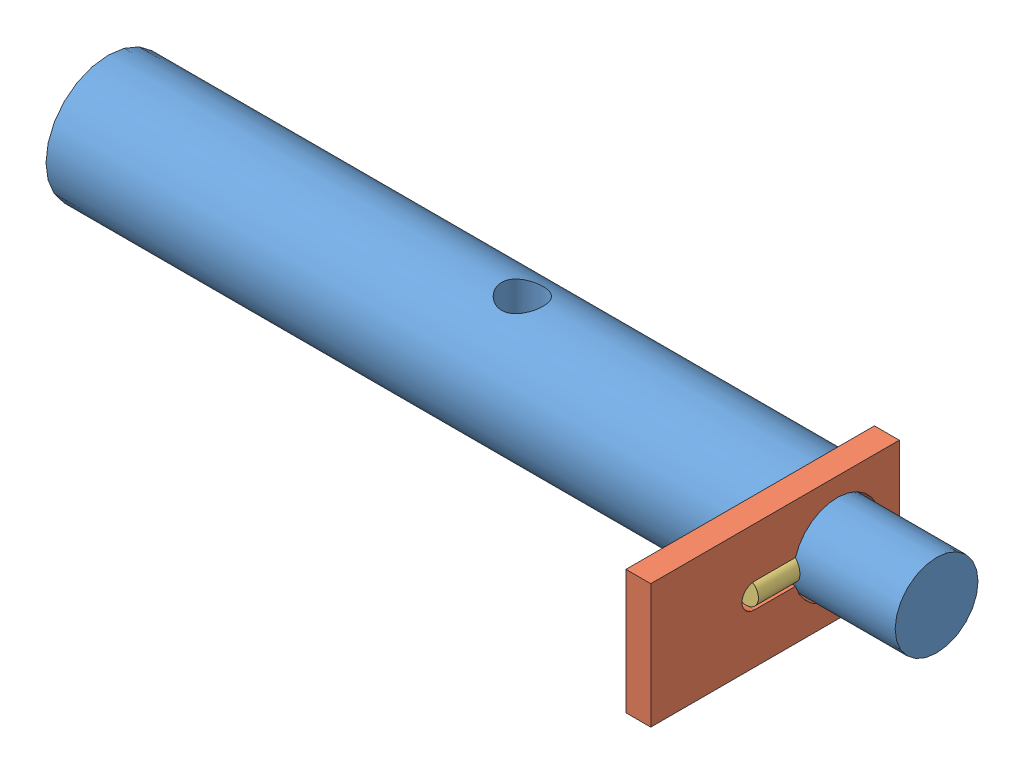
SolidWorks assembly Assemblage1, configuration Défaut. Lengths in mm.
Overall size (100 15 30).
3 component instances, 3 part files, 7 mates.
Components (placement in the parent):
- allonge^Assemblage1-1: allonge^Assemblage1 [Défaut] at origin size (100 15 15) (virtual)
- cale^Assemblage1-1: cale^Assemblage1 [Défaut] at (88 0 0) x (0 -1 0) z (-1 0 0) size (15 30 3) (virtual)
- Goupille^Assemblage1-1: Goupille^Assemblage1 [Défaut] at (87 0 5) x (-1 0 0) z (0 1 0) size (3 10 3) (virtual)
Mates (geometry in assembly coordinates):
- Coaxiale1: concentric anti-aligned: cylinder of allonge^Assemblage1-1 through (87 0 5) axis (0 0 1) radius 1.5; cylinder of Goupille^Assemblage1-1 through (87 0 10) axis (0 0 -1) radius 1.5
- Coïncidente1: coordinate: point of allonge^Assemblage1-1; point of assembly
- Tangent1: tangent aligned: cylinder of allonge^Assemblage1-1 through (85 0 0) axis (1 0 0) radius 5; plane of Goupille^Assemblage1-1 through (87 0 5) normal (0 0 1)
- Parallèle1: parallel aligned: plane of Goupille^Assemblage1-1 through (87 0 5) normal (0 1 0); plane of assembly through (0 0 0) normal (0 1 0)
- Coïncidente2: coincident anti-aligned: plane of allonge^Assemblage1-1 through (85 0 0) normal (1 0 0); plane of cale^Assemblage1-1 through (85 0 0) normal (-1 0 0)
- Coaxiale2: concentric aligned: cylinder of allonge^Assemblage1-1 through (85 0 0) axis (1 0 0) radius 5; cylinder of cale^Assemblage1-1 through (85 0 0) axis (1 0 0) radius 5.25
- Parallèle2: parallel anti-aligned: plane of cale^Assemblage1-1 through (88 0 0) normal (0 -1 0); plane of assembly through (0 0 0) normal (0 1 0)
